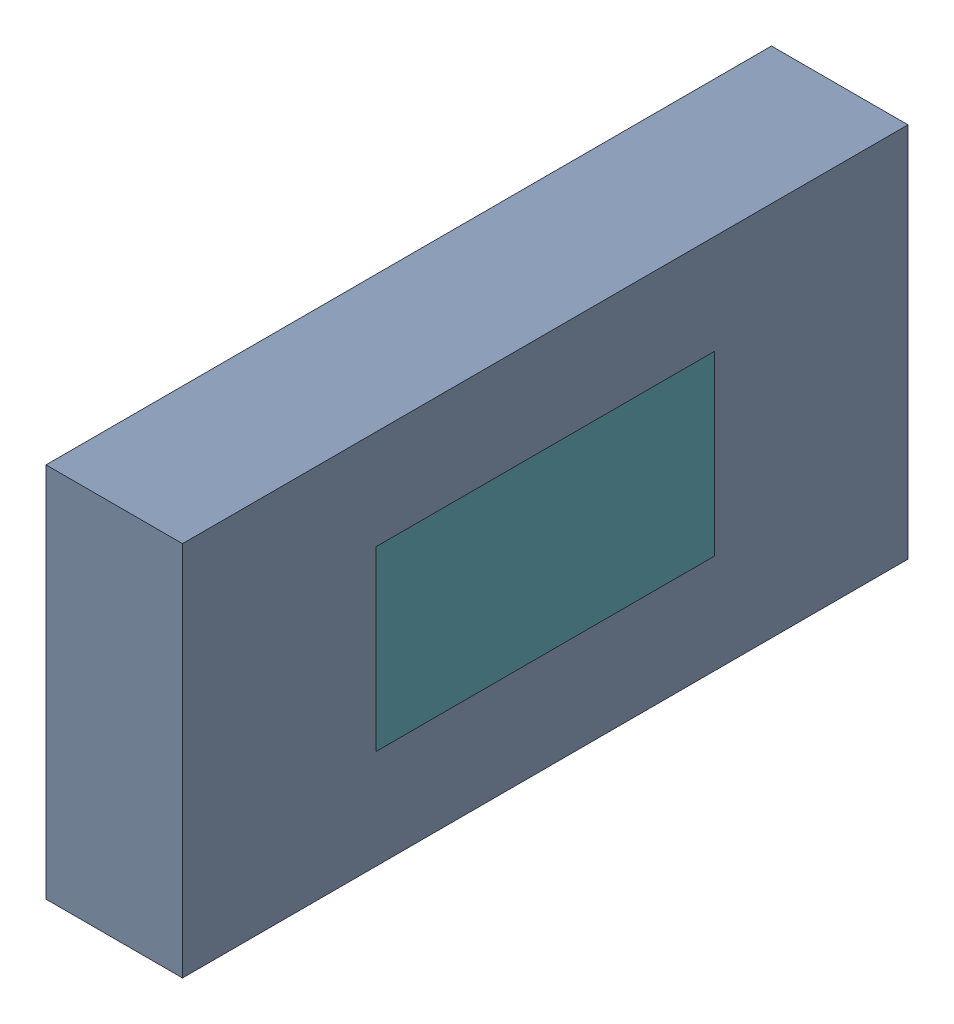
SolidWorks assembly C9, configuration Default. Lengths in mm.
Overall size (0.33 0.7 1.35).
25 component instances, 7 part files, 0 mates.
Components (placement in the parent):
- 6701982208-1:  [Default] at (27.7 14.8 0) (suppressed, hidden)
- 6327398464-1: 6327398464 [Default] at (4.2287 8.85 -1.4931) x (0 0 -1) z (1 0 0) size (1.35 0.7 0.25)
  - 6701982208-1:  [Default] at (27.7 14.8 0) (suppressed, hidden)
  - Extruded-15-1: Extruded-15 [Default] at origin size (1.35 0.7 0.25)
- 6327397888-1: 6327397888 [Default] at (4.2287 8.85 -1.4931) x (0 0 -1) z (1 0 0) size (0.63 0.33 0.25)
  - 6701982208-1:  [Default] at (27.7 14.8 0) (suppressed, hidden)
  - Extruded-16-1: Extruded-16 [Default] at origin size (0.63 0.33 0.25)
- 6327398080-1: 6327398080 [Default] at (4.2287 8.85 -1.4931) x (0 0 -1) z (1 0 0) size (0.73 0.43 0.25)
  - 6701982208-1:  [Default] at (27.7 14.8 0) (suppressed, hidden)
  - Extruded-17-1: Extruded-17 [Default] at origin size (0.73 0.43 0.25)
- 6327398272-1: 6327398272 [Default] at (4.2287 8.85 -1.4931) x (0 0 -1) z (1 0 0) size (1.25 0.6 0.25)
  - 6701982208-1:  [Default] at (27.7 14.8 0) (suppressed, hidden)
  - Extruded-18-1: Extruded-18 [Default] at origin size (1.25 0.6 0.25)
- 6327398464-2: 6327398464 [Default] at (4.2287 8.85 -1.4931) x (0 0 -1) z (1 0 0) size (1.35 0.7 0.25)
  - 6701982208-1:  [Default] at (27.7 14.8 0) (suppressed, hidden)
  - Extruded-15-1: Extruded-15 [Default] at origin size (1.35 0.7 0.25)
- 6327398656-1: 6327398656 [Default] at (4.2287 8.85 -1.4931) x (0 0 -1) z (1 0 0) size (1.15 0.5 0.25)
  - 6701982208-1:  [Default] at (27.7 14.8 0) (suppressed, hidden)
  - Extruded-19-1: Extruded-19 [Default] at origin size (1.15 0.5 0.25)
- 6327398848-1: 6327398848 [Default] at (4.1527 8.85 -1.4931) x (0 0 -1) z (1 0 0) size (0.63 0.33 0.33)
  - 6701982208-1:  [Default] at (27.7 14.8 0) (suppressed, hidden)
  - Extruded-20-1: Extruded-20 [Default] at origin size (0.63 0.33 0.33)
- 6327400768-1: 6327400768 [Default] at (4.2287 8.85 -1.4931) x (0 0 -1) z (1 0 0) size (0.33 0.33 0.25)
  - 6701982208-1:  [Default] at (27.7 14.8 0) (suppressed, hidden)
  - Extruded-6-1: Extruded-6 [Default] at origin size (0.33 0.33 0.25)
